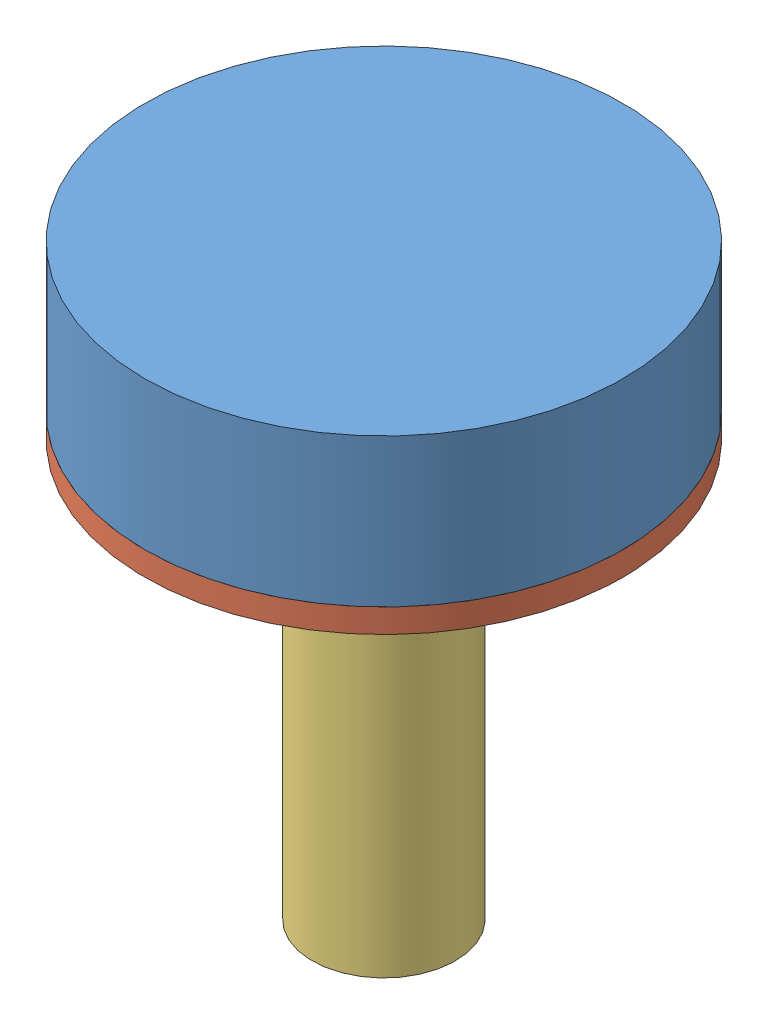
SolidWorks assembly Assemblage1, configuration Défaut. Lengths in mm.
Overall size (100 123 100).
3 component instances, 3 part files, 4 mates.
Components (placement in the parent):
- Pièce1-1: Pièce1 [Défaut] at (-26.3366 7.4065 100) size (100 31 100)
- Pièce2-1: Pièce2 [Défaut] at (-8.6368 -11.3713 123.4257) x (1 0 0) z (0 1 0) size (100 100 5)
- Pièce3-1: Pièce3 [Défaut] at (-50.548 14.6795 151.3477) x (-0.227376 0 0.973807) z (-0.973807 0 -0.227376) size (62 100 62)
Mates (geometry in assembly coordinates):
- Coaxiale1: concentric anti-aligned: cylinder of Pièce2-1 through (-38.5588 -6.3713 100) axis (0 -1 0) radius 15.5; cylinder of Pièce3-1 through (-38.5588 1.6287 100) axis (0 1 0) radius 15
- Coïncidente1: coincident anti-aligned: plane of Pièce2-1 through (-38.5588 -6.3713 100) normal (0 1 0); plane of Pièce3-1 through (-35.1481 -6.3713 85.3929) normal (0 -1 0)
- Coïncidente2: coincident anti-aligned: plane of Pièce1-1 through (-70.0588 -6.3713 100) normal (0 -1 0); plane of Pièce2-1 through (-38.5588 -6.3713 100) normal (0 1 0)
- Coaxiale2: concentric anti-aligned: cylinder of Pièce1-1 through (-38.5588 63.2398 100) axis (0 1 0) radius 50; cylinder of Pièce2-1 through (-38.5588 -6.3713 100) axis (0 -1 0) radius 50
